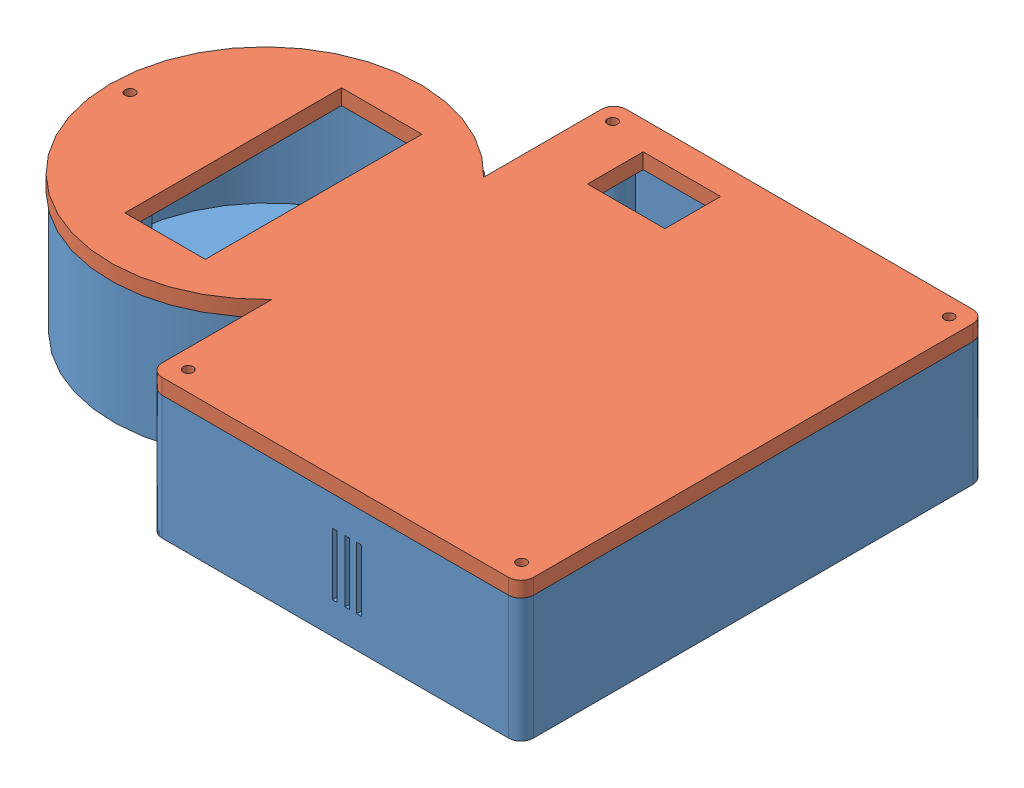
SolidWorks assembly Enclosure, configuration Default. Lengths in mm.
Overall size (1997.6 45 816.96).
2 component instances, 2 part files, 1 mates.
Components (placement in the parent):
- New_Design-2: New_Design [Default] at (-171.1279 1091.5518 1674.4974) size (1743.42 40 816.96)
- New_Design_Lid-2: New_Design_Lid [Default] at (-171.1279 1131.5518 1674.4974) size (1743.42 5 800.06)
Mates (geometry in assembly coordinates):
- Coincident2: coincident aligned: line of New_Design_Lid-2 through (-153.4191 1131.5518 1677.3332) axis (1 0 0); line of New_Design-2 through (-153.4191 1131.5518 1677.3332) axis (1 0 0)
